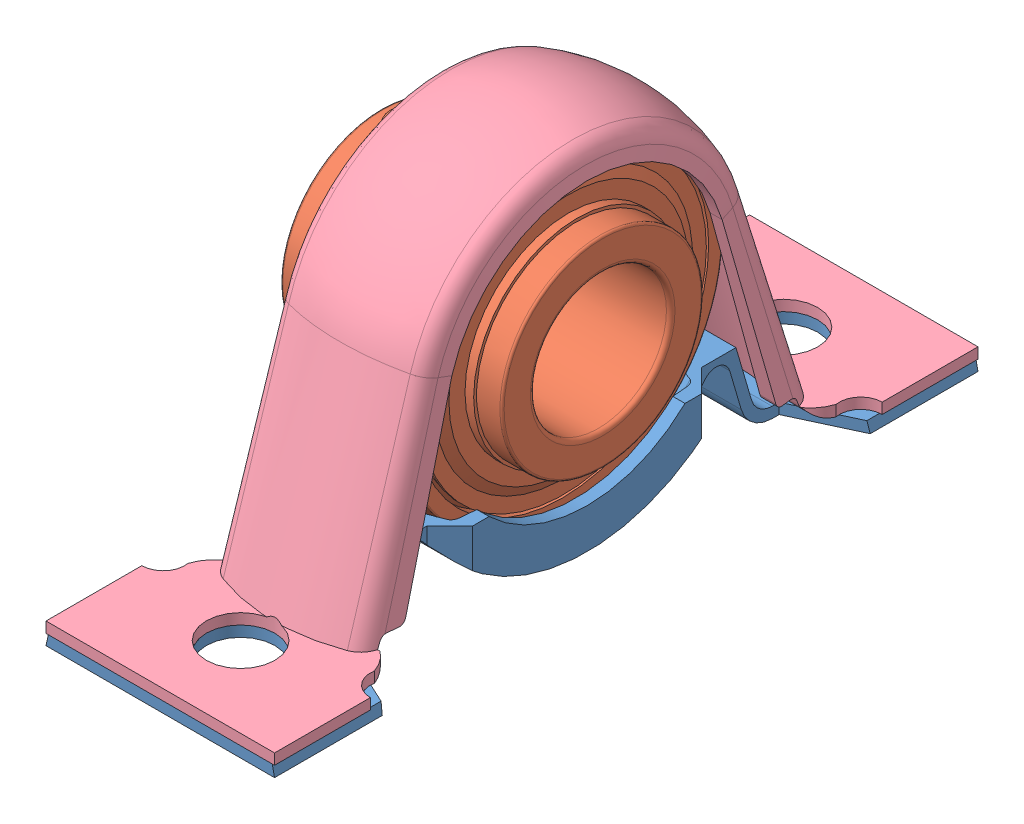
SolidWorks assembly P 3_4 TR, configuration Predeterminado. Lengths in mm.
Overall size (98.5 49.8 98.5).
11 component instances, 4 part files, 0 mates.
Components (placement in the parent):
- housingP 47-housing-1: housingP 47-housing [Predeterminado] x (0 0 1) z (-1 0 0) size (98.5 11.15 32)
- YAR 204-012-2RF-28_2103003912-bearing-1: YAR 204-012-2RF-28_2103003912-bearing [Predeterminado] x (-1 0 0) z (0 0 -1) size (31 47 47)
- 19_05-47-31-14-ybrg1-45 7_938-33_5-ball-1: 19_05-47-31-14-ybrg1-45 7_938-33_5-ball [Predeterminado] at (0 33.5 0) x (1 0 0) z (0 0 -1) size (7.94 7.94 7.94)
- 19_05-47-31-14-ybrg1-45 7_938-33_5-ball-2: 19_05-47-31-14-ybrg1-45 7_938-33_5-ball [Predeterminado] at (0 28.594 -11.844) x (1 0 0) z (0 0 -1) size (7.94 7.94 7.94)
- 19_05-47-31-14-ybrg1-45 7_938-33_5-ball-3: 19_05-47-31-14-ybrg1-45 7_938-33_5-ball [Predeterminado] at (0 16.75 -16.75) x (1 0 0) z (0 0 -1) size (7.94 7.94 7.94)
- 19_05-47-31-14-ybrg1-45 7_938-33_5-ball-4: 19_05-47-31-14-ybrg1-45 7_938-33_5-ball [Predeterminado] at (0 4.906 -11.844) x (1 0 0) z (0 0 -1) size (7.94 7.94 7.94)
- 19_05-47-31-14-ybrg1-45 7_938-33_5-ball-5: 19_05-47-31-14-ybrg1-45 7_938-33_5-ball [Predeterminado] x (1 0 0) z (0 0 -1) size (7.94 7.94 7.94)
- 19_05-47-31-14-ybrg1-45 7_938-33_5-ball-6: 19_05-47-31-14-ybrg1-45 7_938-33_5-ball [Predeterminado] at (0 4.906 11.844) x (1 0 0) z (0 0 -1) size (7.94 7.94 7.94)
- 19_05-47-31-14-ybrg1-45 7_938-33_5-ball-7: 19_05-47-31-14-ybrg1-45 7_938-33_5-ball [Predeterminado] at (0 16.75 16.75) x (1 0 0) z (0 0 -1) size (7.94 7.94 7.94)
- 19_05-47-31-14-ybrg1-45 7_938-33_5-ball-8: 19_05-47-31-14-ybrg1-45 7_938-33_5-ball [Predeterminado] at (0 28.594 11.844) x (1 0 0) z (0 0 -1) size (7.94 7.94 7.94)
- housing2P 47-housing_arc-1: housing2P 47-housing_arc [Predeterminado] x (0 0 -1) z (1 0 0) size (98.5 49 32)
